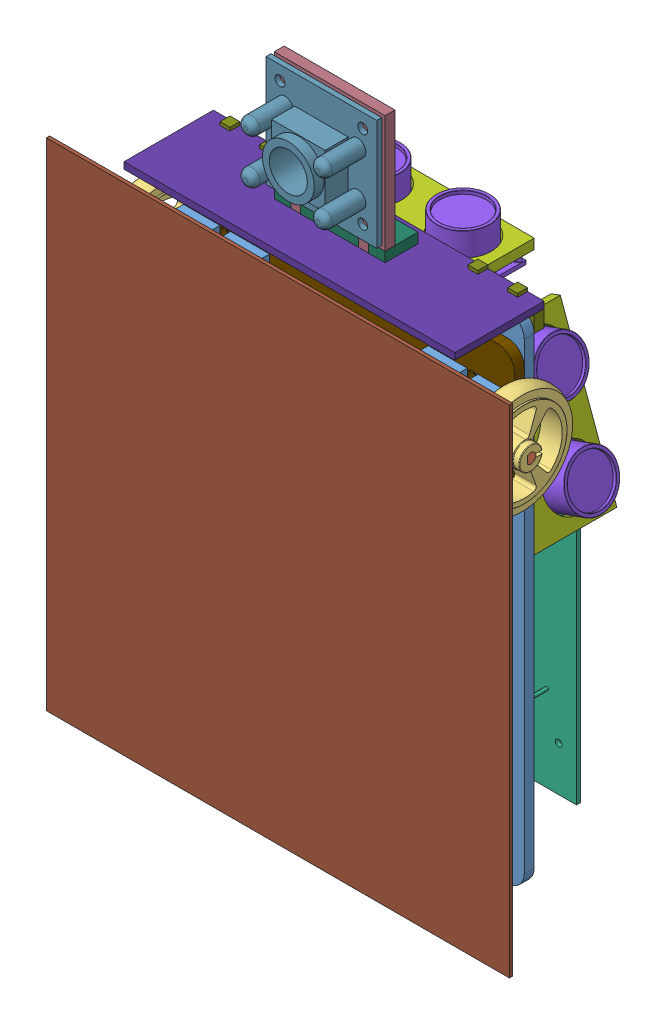
SolidWorks assembly Robot, configuration Default. Lengths in mm.
Overall size (140 204.36 64.38).
130 component instances, 54 part files, 50 mates.
Components (placement in the parent):
- Matična ploča-1: Matična ploča [Default] at (-232.404 -53.1203 167.3302) size (100 150 3)
- arduino uno-1: arduino uno [Default] at (-209.074 -48.1203 153.6802) x (-1 0 0) z (0 -1 0) size (53.34 15.25 74.93)
  - unoboard blue-1: unoboard blue [Default] at origin size (53.34 1.65 68.58)
  - 47uf CAP Dcase-1: 47uf CAP Dcase [Default] at (-9.4141 0 -18.4991) x (0 0 -1) z (1 0 0) size (6.6 5.81 8)
  - USB type b-1: USB type b [Default] at (-38.02 0.43 6.35) size (13.72 15.2 16.5)
    - USB SHELL-1: USB SHELL [Default] at origin size (13.72 15.2 16.5)
    - USB core-1: USB core [Default] at origin size (11.3 10.68 15.75)
    - usb top contact-1: usb top contact [Default] at (1.25 6.09 -0.38) size (1 9.67 13.76)
    - usb btm contact-1: usb btm contact [Default] at (1.25 4.41 -0.38) size (1 6.84 11.76)
    - usb btm contact-2: usb btm contact [Default] at (-1.25 4.41 -0.38) size (1 6.84 11.76)
    - usb top contact-2: usb top contact [Default] at (-1.25 6.09 -0.38) size (1 9.67 13.76)
  - power jack-1: power jack [Default] at (-7.675 0 1.905) size (11.2 15.2 15.9)
  - 47uf CAP Dcase-2: 47uf CAP Dcase [Default] at (-9.4141 0 -25.7132) x (0 0 -1) z (1 0 0) size (6.6 5.81 8)
  - crystal-1: crystal [Default] at (-26.162 0 -18.923) x (1 0 0) z (0 0 -1) size (4 5 11)
  - 2pin_header__02-1: 2pin_header__02 [Default] at (-46.23 0 -15.75) size (5 11.75 2.54)
  - nano - reg-1: nano - reg [Default] at (-17.399 0 -7.747) size (6.5 1.69 8.3)
  - led-1: led [Default] at (-34.29 0 -27.94) x (0 0 1) z (-1 0 0) size (4 0.9 1.55)
  - 2pin_header__02-2: 2pin_header__02 [Default] at (-30.43 0 -64.91) x (0 0 1) z (-1 0 0) size (5 11.75 2.54)
  - dip28-1: dip28 [Default] at (-16.383 1.5 -46.355) x (0 0 -1) z (1 0 0) size (35.48 7.37 10.1)
    - dip28-1: dip28 [Default] at origin size (35.48 2.8 10.1)
    - dip socket pin-1: dip socket pin [Default] at (16.51 2.8 -3.81) size (1.7 7.37 1.7)
    - dip socket pin-2: dip socket pin [Default] at (16.51 2.8 3.81) size (1.7 7.37 1.7)
    - dip socket pin-3: dip socket pin [Default] at (13.97 2.8 -3.81) size (1.7 7.37 1.7)
    - dip socket pin-4: dip socket pin [Default] at (13.97 2.8 3.81) size (1.7 7.37 1.7)
    - dip socket pin-5: dip socket pin [Default] at (11.43 2.8 -3.81) size (1.7 7.37 1.7)
    - dip socket pin-6: dip socket pin [Default] at (11.43 2.8 3.81) size (1.7 7.37 1.7)
    - dip socket pin-7: dip socket pin [Default] at (8.89 2.8 -3.81) size (1.7 7.37 1.7)
    - dip socket pin-8: dip socket pin [Default] at (8.89 2.8 3.81) size (1.7 7.37 1.7)
    - dip socket pin-9: dip socket pin [Default] at (6.35 2.8 -3.81) size (1.7 7.37 1.7)
    - dip socket pin-10: dip socket pin [Default] at (6.35 2.8 3.81) size (1.7 7.37 1.7)
    - dip socket pin-11: dip socket pin [Default] at (3.81 2.8 -3.81) size (1.7 7.37 1.7)
    - dip socket pin-12: dip socket pin [Default] at (3.81 2.8 3.81) size (1.7 7.37 1.7)
    - dip socket pin-13: dip socket pin [Default] at (1.27 2.8 -3.81) size (1.7 7.37 1.7)
    - dip socket pin-14: dip socket pin [Default] at (1.27 2.8 3.81) size (1.7 7.37 1.7)
    - dip socket pin-15: dip socket pin [Default] at (-1.27 2.8 -3.81) size (1.7 7.37 1.7)
    - dip socket pin-16: dip socket pin [Default] at (-1.27 2.8 3.81) size (1.7 7.37 1.7)
    - dip socket pin-17: dip socket pin [Default] at (-3.81 2.8 -3.81) size (1.7 7.37 1.7)
    - dip socket pin-18: dip socket pin [Default] at (-3.81 2.8 3.81) size (1.7 7.37 1.7)
    - dip socket pin-19: dip socket pin [Default] at (-6.35 2.8 -3.81) size (1.7 7.37 1.7)
    - dip socket pin-20: dip socket pin [Default] at (-6.35 2.8 3.81) size (1.7 7.37 1.7)
    - dip socket pin-21: dip socket pin [Default] at (-8.89 2.8 -3.81) size (1.7 7.37 1.7)
    - dip socket pin-22: dip socket pin [Default] at (-8.89 2.8 3.81) size (1.7 7.37 1.7)
    - dip socket pin-23: dip socket pin [Default] at (-11.43 2.8 -3.81) size (1.7 7.37 1.7)
    - dip socket pin-24: dip socket pin [Default] at (-11.43 2.8 3.81) size (1.7 7.37 1.7)
    - dip socket pin-25: dip socket pin [Default] at (-13.97 2.8 -3.81) size (1.7 7.37 1.7)
    - dip socket pin-26: dip socket pin [Default] at (-13.97 2.8 3.81) size (1.7 7.37 1.7)
    - dip socket pin-27: dip socket pin [Default] at (-16.51 2.8 -3.81) size (1.7 7.37 1.7)
    - dip socket pin-28: dip socket pin [Default] at (-16.51 2.8 3.81) size (1.7 7.37 1.7)
  - 2pin_header__02-3: 2pin_header__02 [Default] at (-27.89 0 -64.91) x (0 0 1) z (-1 0 0) size (5 11.75 2.54)
  - 2pin_header__02-4: 2pin_header__02 [Default] at (-25.35 0 -64.91) x (0 0 1) z (-1 0 0) size (5 11.75 2.54)
  - 2pin_header__02-5: 2pin_header__02 [Default] at (-46.23 0 -18.29) size (5 11.75 2.54)
  - 2pin_header__02-6: 2pin_header__02 [Default] at (-46.23 0 -20.83) size (5 11.75 2.54)
  - atmega16u2-1: atmega16u2 [Default] at (-34.671 0.06 -20) x (1 0 0) z (0 0 -1) size (5.5 1.01 5.5)
  - led-2: led [Default] at (-36.83 0 -27.94) x (0 0 1) z (-1 0 0) size (4 0.9 1.55)
  - led-3: led [Default] at (-42.037 0 -27.94) x (0 0 1) z (-1 0 0) size (4 0.9 1.55)
  - led-4: led [Default] at (-36.576 0 -58.42) x (0 0 1) z (-1 0 0) size (4 0.9 1.55)
  - 8 PORT HEADER-1: 8 PORT HEADER [Default] at (-50.8 0 -45.72) x (0 0 -1) z (1 0 0) size (20.32 10.51 2.41)
  - 8 PORT HEADER-2: 8 PORT HEADER [Default] at (-2.54 0 -27.94) x (0 0 -1) z (1 0 0) size (20.32 10.51 2.41)
  - 6 PORT HEADER-1: 6 PORT HEADER [Default] at (-2.54 0 -50.8) x (0 0 -1) z (1 0 0) size (15.24 10.51 2.41)
  - 10 PORT HEADER-1: 10 PORT HEADER [Default] at (-50.8 0 -18.796) x (0 0 -1) z (1 0 0) size (25.4 10.51 2.41)
  - ATMEL328P-1: ATMEL328P [Default] at (-16.383 4.3 -46.355) x (0 0 -1) z (1 0 0) size (35 7.27 7.87)
  - 102 RESISTOR PACK-1: 102 RESISTOR PACK [Default] at (-33.782 0 -58.42) size (3.2 0.51 3)
  - 102 RESISTOR PACK-2: 102 RESISTOR PACK [Default] at (-39.37 0 -27.94) size (3.2 0.51 3)
  - 103 RESISTOR PACK-1: 103 RESISTOR PACK [Default] at (-23.876 0 -27.94) size (3.2 0.51 3)
  - 220 RESISTOR PACK-1: 220 RESISTOR PACK [Default] at (-36.83 0 -12.827) size (3.2 0.51 3)
  - 16mhz crystal - measured-1: 16mhz crystal - measured [Default] at (-24.892 0 -41.275) x (0 0 -1) z (1 0 0) size (3.4 0.8 2)
  - PADS001-1: PADS001 [Default] at (-39.878 0.1 -18.288) x (-1 0 0) z (0 0 1) size (4.54 0.1 4.54)
  - 603 cap on pad-1: 603 cap on pad [Default] at (-44.45 0 -27.94) x (0 0 -1) z (1 0 0) size (2.76 0.9 1.02)
  - ssot3-1: ssot3 [Default] at (-26.5 0 -8.128) x (-1 0 0) z (0 0 -1) size (3 1.13 3.09)
  - mf-msmf050-2-1: mf-msmf050-2 [Default] at (-26.5 0 -4.064)
  - 603 cap on pad-2: 603 cap on pad [Default] at (-29.845 0 -27.94) x (0 0 -1) z (1 0 0) size (2.76 0.9 1.02)
  - 603 cap on pad-3: 603 cap on pad [Default] at (-31.496 0 -27.94) x (0 0 -1) z (1 0 0) size (2.76 0.9 1.02)
  - lmv358-1: lmv358 [Default] at (-15.24 0 -21.971) x (0 0 -1) z (1 0 0) size (3.7 1.4 2.9)
  - 603 cap on pad-4: 603 cap on pad [Default] at (-15.24 0 -18.415) size (2.76 0.9 1.02)
  - 603 cap on pad-5: 603 cap on pad [Default] at (-29.845 0 -12.065) x (0 0 1) z (-1 0 0) size (2.76 0.9 1.02)
  - 603 cap on pad-6: 603 cap on pad [Default] at (-29.591 0 -22.352) x (0 0 1) z (-1 0 0) size (2.76 0.9 1.02)
  - 603 cap on pad-7: 603 cap on pad [Default] at (-29.591 0 -16.002) x (0 0 1) z (-1 0 0) size (2.76 0.9 1.02)
  - 603 cap on pad-8: 603 cap on pad [Default] at (-41.91 0 -12.7) x (0 0 1) z (-1 0 0) size (2.76 0.9 1.02)
  - lp2985dgkr-1: lp2985dgkr [Default] at (-20.32 0 -19.05) x (0 0 -1) z (1 0 0) size (5.85 1.1 3)
  - cd1206 diode-1: cd1206 diode [Default] at (-27.94 0 -59.436) x (0 0 -1) z (1 0 0) size (2.08 0.96 5)
  - cd1206 diode-2: cd1206 diode [Default] at (-46.228 0 -13.081) x (0 0 1) z (-1 0 0) size (2.08 0.96 5)
  - 603 resistor-1: 603 resistor [Default] at (-29.591 0 -19.05) x (0 0 1) z (-1 0 0) size (2.36 0.62 1.04)
  - blm21-1: blm21 [Default] at (-45.085 0 -7.62) x (0 0 -1) z (1 0 0) size (2.78 0.95 1.32)
  - m7 diode-1: m7 diode [Default] at (-2.794 0 -21.59) x (0 0 -1) z (1 0 0) size (6.66 2.35 2.5)
  - MLC0603-1: MLC0603 [Default] at (-33.655 0 -12.827) x (0 0 -1) z (1 0 0) size (2.36 0.6 1.04)
  - MLC0603-2: MLC0603 [Default] at (-39.37 0 -12.827) x (0 0 -1) z (1 0 0) size (2.36 0.6 1.04)
  - RESET BUTTON-1: RESET BUTTON [Default] at (-49.403 0 -6.35) size (6.2 3.1 9.6)
    - RESET CORE-1: RESET CORE [Default] at (0 0.1 0) x (-1 0 0) z (0 0 -1) size (6.2 3.1 9.6)
    - RESET-1: RESET [Default] at (0 0.1 0) x (0 0 1) z (-1 0 0) size (7.3 2 6.2)
- Nosač točkova-2: Nosač točkova [Default] at (-217.8597 19.6248 92.6573) size (120.02 45.03 45.03)
  - Osnovna ploča-1: Osnovna ploča [Default] at (-14.5443 30.0854 77.673) size (100 40 3)
  - Bočna duža-1: Bočna duža [Default] at (-14.5443 41.0854 90.673) x (1 0 0) z (0 1 0) size (26 15.6 3)
  - Bočna duža-2: Bočna duža [Default] at (-14.5443 56.0854 90.673) x (1 0 0) z (0 1 0) size (26 15.6 3)
  - Bočna duža-3: Bočna duža [Default] at (85.4557 44.0854 90.673) x (-1 0 0) z (0 -1 0) size (26 15.6 3)
  - Bočna duža-4: Bočna duža [Default] at (85.4557 59.0854 90.673) x (-1 0 0) z (0 -1 0) size (26 15.6 3)
  - Motor sa točkovima-1: Motor sa točkovima [Default] at (50.8926 62.8706 105.4705) x (0 -1 0) z (1 0 0) size (45.03 45.03 35.61)
    - DC motor-1: DC motor [Default] at (6.7852 14.7976 10.3631) size (12 10 35.6)
    - Točak-1: Točak [Default] at (12.7852 19.7976 36.0631) x (0.766044 0.642788 0) z (0 0 1) size (31.97 31.97 8.51)
  - Motor sa točkovima-2: Motor sa točkovima [Default] at (20.0188 62.8706 65.8754) x (0 -1 0) z (-1 0 0) size (45.03 45.03 35.61)
    - DC motor-1: DC motor [Default] at (6.7852 14.7976 10.3631) size (12 10 35.6)
    - Točak-1: Točak [Default] at (12.7852 19.7976 36.0631) x (0.766044 0.642788 0) z (0 0 1) size (31.97 31.97 8.51)
  - Donji držač motora-1: Donji držač motora [Default] at (-14.5443 41.0854 90.673) size (26 18 3)
  - Donji držač motora-2: Donji držač motora [Default] at (59.4557 41.0854 90.673) size (26 18 3)
- Odstojnik šestougaoni-1: Odstojnik šestougaoni [Default] at (-158.274 -32.8803 155.3302) size (5 5.77 16)
- Odstojnik šestougaoni-2: Odstojnik šestougaoni [Default] at (-206.534 -34.1503 155.3302) size (5 5.77 16)
- Odstojnik šestougaoni-3: Odstojnik šestougaoni [Default] at (-201.454 17.9197 155.3302) size (5 5.77 16)
- Odstojnik šestougaoni-4: Odstojnik šestougaoni [Default] at (-173.514 17.9197 155.3302) size (5 5.77 16)
- Zuma pločica-1: Zuma pločica [Default] at (-149.274 -54.8219 136.4702) x (0 1 0) z (0 0 1) size (83 66 9.2)
- Ultrazvučni senzor sklop-1: Ultrazvučni senzor sklop [Default] at (-171.5702 59.4522 126.6855) x (-0.34202 -0.939693 0) z (-0.939693 0.34202 0) size (50 30.8 26.8)
  - Nosač ultrazvučnog senzora duža-1: Nosač ultrazvučnog senzora duža [Default] at (-5.1634 15.6447 45.4188) size (50 25 3)
  - Ultrazvučni senzor-1: Ultrazvučni senzor [Default] at (-2.6634 15.6447 40.2188) size (45 25.8 20)
  - Nosač ultrazvučnog senzora kraća-1: Nosač ultrazvučnog senzora kraća [Default] at (-5.1634 40.6447 28.4188) x (1 0 0) z (0 -1 0) size (50 20 3)
- Ultrazvučni senzor sklop-2: Ultrazvučni senzor sklop [Default] at (-179.6688 22.1715 126.6855) x (-0.34202 0.939693 0) z (0.939693 0.34202 0) size (50 30.8 26.8)
  - Nosač ultrazvučnog senzora duža-1: Nosač ultrazvučnog senzora duža [Default] at (-5.1634 15.6447 45.4188) size (50 25 3)
  - Ultrazvučni senzor-1: Ultrazvučni senzor [Default] at (-2.6634 15.6447 40.2188) size (45 25.8 20)
  - Nosač ultrazvučnog senzora kraća-1: Nosač ultrazvučnog senzora kraća [Default] at (-5.1634 40.6447 28.4188) x (1 0 0) z (0 -1 0) size (50 20 3)
- Ultrazvučni senzor sklop-3: Ultrazvučni senzor sklop [Default] at (-162.5674 43.4609 126.6855) x (-1 0 0) z (0 1 0) size (50 30.8 26.8)
  - Nosač ultrazvučnog senzora duža-1: Nosač ultrazvučnog senzora duža [Default] at (-5.1634 15.6447 45.4188) size (50 25 3)
  - Ultrazvučni senzor-1: Ultrazvučni senzor [Default] at (-2.6634 15.6447 40.2188) size (45 25.8 20)
  - Nosač ultrazvučnog senzora kraća-1: Nosač ultrazvučnog senzora kraća [Default] at (-5.1634 40.6447 28.4188) x (1 0 0) z (0 -1 0) size (50 20 3)
- Kuglica-1: Kuglica [Default] at (-182.4048 -37.1203 173.3302) x (0.811311 0.584615 0) z (0 0 1) size (48.2 32 20.5)
- Podloga-1: Podloga [Default] at (-112.404 -53.1203 193.8302) x (0 1 0) z (0 0 1) size (150 140 1)
- Podmetač za kuglicu-1: Podmetač za kuglicu [Default] at (-182.4048 -37.1203 170.3302) x (0.811311 0.584615 0) z (0 0 1) size (52.2 36 3)
- Sklop-1: Sklop [Default] at (-170.57 136.9131 145.4939) x (-1 0 0) z (0 0 1) size (33.5 38.5 24.5)
  - Nosač-1: Nosač [Default] at (-4.0762 -0.4666 29.8363) size (33.5 38.5 3)
  - Kolor senzor-1: Kolor senzor [Default] at (-4.0762 -0.4666 33.8363) size (33.5 33.5 21.7)
  - Bočna kraća-1: Bočna kraća [Default] at (-4.0762 38.0334 22.8363) x (1 0 0) z (0 -1 0) size (33.5 10 3)
- Prva stranica-1: Prva stranica [Default] at (-211.9981 91.8797 156.3396) size (25 8 3)
- Prva stranica-2: Prva stranica [Default] at (-286.9981 91.8797 156.3396) size (25 8 3)
- Druga stranica-1: Druga stranica [Default] at (-232.404 96.8797 191.3302) x (1 0 0) z (0 1 0) size (100 27 2)
Mates (geometry in assembly coordinates):
- Distance1: distance = 12 mm anti-aligned: plane of arduino uno-1/unoboard blue-1 through (-209.074 -48.1203 155.3302) normal (0 0 1); plane of Matična ploča-1 through (-232.404 -53.1203 167.3302) normal (0 0 -1)
- Distance2: distance = 5 mm aligned: plane of arduino uno-1/unoboard blue-1 through (-209.074 -48.1203 155.3302) normal (0 -1 0); plane of Matična ploča-1 through (-232.404 -53.1203 170.3302) normal (0 -1 0)
- Distance3: distance = 23.33 mm aligned: plane of arduino uno-1/unoboard blue-1 through (-209.074 -48.1203 155.3302) normal (-1 0 0); plane of Matična ploča-1 through (-232.404 -53.1203 170.3302) normal (-1 0 0)
- Coincident1: coincident aligned: plane of Matična ploča-1 through (-132.404 -53.1203 170.3302) normal (1 0 0); plane of Nosač točkova-2/Osnovna ploča-1 through (-132.404 49.7102 173.3302) normal (1 0 0)
- Coincident2: coincident anti-aligned: plane of Matična ploča-1 through (-232.404 -53.1203 170.3302) normal (0 0 1); plane of Nosač točkova-2/Osnovna ploča-1 through (-232.404 49.7102 170.3302) normal (0 0 -1)
- LimitDistance1: limit distance = 7.1695 mm aligned: plane of Nosač točkova-2/Osnovna ploča-1 through (-232.404 89.7102 173.3302) normal (0 1 0); plane of Matična ploča-1 through (-232.404 96.8797 170.3302) normal (0 1 0)
- Concentric1: concentric aligned: circle of Matična ploča-1; cylinder of Odstojnik šestougaoni-1 through (-158.274 -32.8803 169.3302) axis (0 0 -1) radius 1.5
- Coincident4: coincident anti-aligned: plane of Matična ploča-1 through (-232.404 -53.1203 167.3302) normal (0 0 -1); plane of Odstojnik šestougaoni-1 through (-158.274 -32.8803 167.3302) normal (0 0 1)
- Concentric2: concentric aligned: circle of Matična ploča-1; cylinder of Odstojnik šestougaoni-2 through (-206.534 -34.1503 169.3302) axis (0 0 -1) radius 1.5
- Coincident5: coincident anti-aligned: plane of Matična ploča-1 through (-232.404 -53.1203 167.3302) normal (0 0 -1); plane of Odstojnik šestougaoni-2 through (-206.534 -34.1503 167.3302) normal (0 0 1)
- Concentric3: concentric aligned: circle of Matična ploča-1; cylinder of Odstojnik šestougaoni-3 through (-201.454 17.9197 169.3302) axis (0 0 -1) radius 1.5
- Coincident6: coincident anti-aligned: plane of Matična ploča-1 through (-232.404 -53.1203 167.3302) normal (0 0 -1); plane of Odstojnik šestougaoni-3 through (-201.454 17.9197 167.3302) normal (0 0 1)
- Concentric4: concentric aligned: cylinder of Matična ploča-1 through (-173.514 17.9197 170.3302) axis (0 0 -1) radius 1.5875; cylinder of Odstojnik šestougaoni-4 through (-173.514 17.9197 169.3302) axis (0 0 -1) radius 1.5
- Coincident7: coincident anti-aligned: plane of Matična ploča-1 through (-232.404 -53.1203 167.3302) normal (0 0 -1); plane of Odstojnik šestougaoni-4 through (-173.514 17.9197 167.3302) normal (0 0 1)
- Coincident8: coincident: line of arduino uno-1/10 PORT HEADER-1 through (-158.774 -28.8243 145.6702) axis (0 0 1); cylinder of Zuma pločica-1 through (-158.274 -28.8219 145.6702) axis (0 0 -1) radius 0.5
- Coincident9: coincident: line of arduino uno-1/10 PORT HEADER-1 through (-157.774 -28.8243 145.6702) axis (-1 0 0); plane of Zuma pločica-1 through (-158.274 -28.8219 145.6702) normal (0 0 1)
- Parallel1: parallel aligned: plane of arduino uno-1/unoboard blue-1 through (-155.734 -48.1203 155.3302) normal (1 0 0); plane of Zuma pločica-1 through (-149.274 -54.8219 137.6702) normal (1 0 0)
- Coincident10: coincident anti-aligned: plane of Matična ploča-1 through (-232.404 -53.1203 167.3302) normal (0 0 -1); plane of Ultrazvučni senzor sklop-1/Nosač ultrazvučnog senzora kraća-1 through (-196.5091 74.0239 167.3302) normal (0 0 1)
- Coincident13: coincident anti-aligned: plane of Matična ploča-1 through (-232.404 -53.1203 167.3302) normal (0 0 -1); plane of Ultrazvučni senzor sklop-2/Nosač ultrazvučnog senzora kraća-1 through (-151.1979 27.0393 167.3302) normal (0 0 1)
- Coincident16: coincident anti-aligned: plane of Matična ploča-1 through (-232.404 -53.1203 167.3302) normal (0 0 -1); plane of Ultrazvučni senzor sklop-3/Nosač ultrazvučnog senzora kraća-1 through (-157.404 71.8797 167.3302) normal (0 0 1)
- Coincident17: coincident aligned: plane of Matična ploča-1 through (-157.404 91.8797 167.3302) normal (0 1 0); plane of Ultrazvučni senzor sklop-3/Nosač ultrazvučnog senzora duža-1 through (-157.404 91.8797 142.3302) normal (0 1 0)
- Coincident18: coincident: line of Matična ploča-1 through (-157.404 91.8797 167.3302) axis (0 0 1); plane of Ultrazvučni senzor sklop-3/Nosač ultrazvučnog senzora duža-1 through (-157.404 91.8797 142.3302) normal (0 1 0)
- Coincident19: coincident anti-aligned: line of Matična ploča-1 through (-157.404 91.8797 167.3302) axis (0 0 1); line of Ultrazvučni senzor sklop-3/Nosač ultrazvučnog senzora duža-1 through (-157.404 91.8797 167.3302) axis (0 0 -1)
- Coincident20: coincident: plane of Matična ploča-1 through (-232.404 -53.1203 170.3302) normal (-1 0 0); line of Ultrazvučni senzor sklop-1/Nosač ultrazvučnog senzora duža-1 through (-232.404 33.8797 142.3302) axis (0 0 1)
- Angle1: planar angle = 2.792527 rad aligned: line of Ultrazvučni senzor sklop-1/Nosač ultrazvučnog senzora duža-1 through (-232.404 33.8797 167.3302) axis (0.34202 0.939693 0); line of Matična ploča-1 through (-232.404 91.8797 167.3302) axis (0 -1 0)
- Coincident22: coincident: plane of Matična ploča-1 through (-132.404 -53.1203 170.3302) normal (1 0 0); line of Ultrazvučni senzor sklop-2/Nosač ultrazvučnog senzora duža-1 through (-132.404 33.8797 167.3302) axis (0 0 -1)
- Angle2: planar angle = 2.792527 rad aligned: line of Ultrazvučni senzor sklop-2/Nosač ultrazvučnog senzora duža-1 through (-145.0587 68.6483 167.3302) axis (0.34202 -0.939693 0); line of Matična ploča-1 through (-132.404 -48.1203 167.3302) axis (0 1 0)
- Distance6: distance = 58 mm: line of Matična ploča-1 through (-232.404 91.8797 170.3302) axis (0 0 -1); line of Ultrazvučni senzor sklop-1/Nosač ultrazvučnog senzora duža-1 through (-232.404 33.8797 142.3302) axis (0 0 1)
- Distance8: distance = 58 mm: line of Matična ploča-1 through (-132.404 91.8797 167.3302) axis (0 0 1); line of Ultrazvučni senzor sklop-2/Nosač ultrazvučnog senzora duža-1 through (-132.404 33.8797 167.3302) axis (0 0 -1)
- Distance10: distance = 3 mm anti-aligned: plane of Matična ploča-1 through (-232.404 -53.1203 170.3302) normal (0 0 1); plane of Kuglica-1 through (-198.2254 -48.5203 173.3302) normal (0 0 -1)
- Coincident28: coincident aligned: plane of Matična ploča-1 through (-232.404 -53.1203 170.3302) normal (0 -1 0); plane of Kuglica-1 through (-198.2254 -53.1203 174.3302) normal (0 -1 0)
- Distance9: distance = 29.815 mm: line of Kuglica-1 through (-202.589 -47.0646 174.3302) axis (0 0 -1); plane of Matična ploča-1 through (-232.404 -53.1203 170.3302) normal (-1 0 0)
- Distance11: distance = 20 mm aligned: plane of Matična ploča-1 through (-132.404 -53.1203 170.3302) normal (1 0 0); plane of Podloga-1 through (-112.404 -53.1203 194.8302) normal (1 0 0)
- Coincident30: coincident aligned: plane of Matična ploča-1 through (-232.404 -53.1203 170.3302) normal (0 -1 0); plane of Podloga-1 through (-112.404 -53.1203 194.8302) normal (0 -1 0)
- Tangent1: tangent anti-aligned: sphere of Kuglica-1; plane of Podloga-1 through (-112.404 -53.1203 193.8302) normal (0 0 -1)
- Coincident31: coincident anti-aligned: plane of Matična ploča-1 through (-232.404 -53.1203 170.3302) normal (0 0 1); plane of Podmetač za kuglicu-1 through (-182.4048 -37.1203 170.3302) normal (0 0 -1)
- Concentric5: concentric anti-aligned: cylinder of Matična ploča-1 through (-198.2254 -48.5203 167.3302) axis (0 0 1) radius 1.5; cylinder of Podmetač za kuglicu-1 through (-198.2254 -48.5203 173.3302) axis (0 0 -1) radius 2
- Concentric6: concentric anti-aligned: circle of Matična ploča-1; cylinder of Podmetač za kuglicu-1 through (-166.5843 -25.7203 173.3302) axis (0 0 -1) radius 2
- Distance12: distance = 13 mm anti-aligned: plane of Sklop-1/Kolor senzor-1 through (-166.4938 137.3797 180.8302) normal (0 0 1); plane of Podloga-1 through (-112.404 -53.1203 193.8302) normal (0 0 -1)
- Parallel2: parallel anti-aligned: plane of Matična ploča-1 through (-232.404 96.8797 170.3302) normal (0 1 0); plane of Sklop-1/Bočna kraća-1 through (-166.4938 98.8797 168.3302) normal (0 -1 0)
- Coincident35: coincident anti-aligned: plane of Matična ploča-1 through (-232.404 -53.1203 167.3302) normal (0 0 -1); plane of Prva stranica-2 through (-286.9981 91.8797 167.3302) normal (0 0 1)
- Coincident36: coincident aligned: plane of Matična ploča-1 through (-232.404 -53.1203 170.3302) normal (-1 0 0); plane of Prva stranica-2 through (-232.404 96.8797 164.3302) normal (-1 0 0)
- Coincident37: coincident aligned: plane of Matična ploča-1 through (-232.404 96.8797 170.3302) normal (0 1 0); plane of Prva stranica-2 through (-215.404 96.8797 164.3302) normal (0 1 0)
- Coincident38: coincident anti-aligned: plane of Prva stranica-1 through (-132.404 96.8797 164.3302) normal (0 1 0); plane of Druga stranica-1 through (-232.404 96.8797 191.3302) normal (0 -1 0)
- Coincident39: coincident aligned: plane of Prva stranica-1 through (-132.404 91.8797 164.3302) normal (1 0 0); plane of Druga stranica-1 through (-132.404 98.8797 191.3302) normal (1 0 0)
- Coincident40: coincident aligned: plane of Matična ploča-1 through (-232.404 96.8797 170.3302) normal (0 1 0); plane of Prva stranica-1 through (-140.404 96.8797 164.3302) normal (0 1 0)
- Coincident41: coincident aligned: plane of Matična ploča-1 through (-132.404 -53.1203 170.3302) normal (1 0 0); plane of Prva stranica-1 through (-132.404 91.8797 164.3302) normal (1 0 0)
- Coincident42: coincident anti-aligned: plane of Matična ploča-1 through (-232.404 -53.1203 167.3302) normal (0 0 -1); plane of Prva stranica-1 through (-211.9981 91.8797 167.3302) normal (0 0 1)
- Coincident43: coincident aligned: plane of Prva stranica-1 through (-211.9981 91.8797 164.3302) normal (0 0 -1); plane of Druga stranica-1 through (-232.404 98.8797 164.3302) normal (0 0 -1)
- Coincident44: coincident anti-aligned: plane of Sklop-1/Bočna kraća-1 through (-166.4938 98.8797 168.3302) normal (0 -1 0); plane of Druga stranica-1 through (-232.404 98.8797 191.3302) normal (0 1 0)
